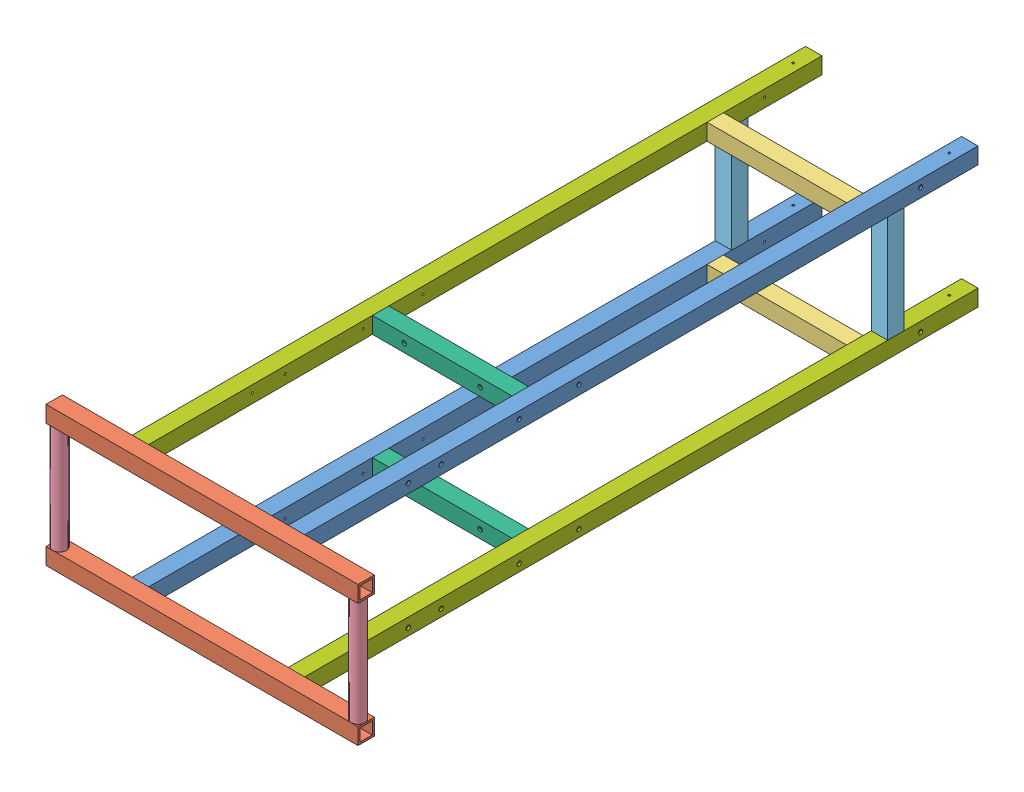
SolidWorks assembly GE-18054, configuration Default. Lengths in mm.
Overall size (978.32 431.8 2141.5).
14 component instances, 7 part files, 46 mates.
Components (placement in the parent):
- GE-18054-1-1: GE-18054-1 [Default] at (-50.8 0 0) size (50.8 50.8 2082.8)
- GE-18054-1-2: GE-18054-1 [Default] at (50.8 0 0) x (-1 0 0) z (0 0 1) size (50.8 50.8 2082.8)
- GE-18054-7-1: GE-18054-7 [Default] at (-266.7 -381 0) x (0 -1 0) z (0 0 1) size (50.8 965.2 50.8)
- GE-18054-7-2: GE-18054-7 [Default] at (-266.7 0 0) x (0 -1 0) z (0 0 1) size (50.8 965.2 50.8)
- GE-18054-3-1: GE-18054-3 [Default] at (-50.8 -381 304.8) x (0 -1 0) z (0 0 1) size (50.8 431.8 50.8)
- GE-18054-3-2: GE-18054-3 [Default] at (50.8 381 304.8) x (0 1 0) z (0 0 1) size (50.8 431.8 50.8)
- GE-18054-6-1: GE-18054-6 [Default] at (-1502.8409 0 1311.2812) x (0 -1 0) z (0.956707 0 0.291052) size (330.2 42.16 42.16)
- GE-18054-6-2: GE-18054-6 [Default] at (474.15 0 4016.5169) x (0 -1 0) z (-0.521598 0 -0.853191) size (330.2 42.16 42.16)
- GE-18054-5-1: GE-18054-5 [Default] at (431.8 0 228.6) x (0 -1 0) z (0 0 1) size (330.2 50.8 50.8)
- GE-18054-5-2: GE-18054-5 [Default] at (-431.8 0 228.6) x (0 1 0) z (0 0 1) size (330.2 50.8 50.8)
- GE-18054-4-1: GE-18054-4 [Default] at (50.8 381 781.05) x (0 1 0) z (0 0 1) size (50.8 431.8 50.8)
- GE-18054-4-2: GE-18054-4 [Default] at (-50.8 -381 781.05) x (0 -1 0) z (0 0 1) size (50.8 431.8 50.8)
- GE-18054-2-1: GE-18054-2 [Default] at (-50.8 0 0) size (50.8 50.8 2082.8)
- GE-18054-2-2: GE-18054-2 [Default] at (50.8 0 0) x (-1 0 0) z (0 0 1) size (50.8 50.8 2082.8)
Mates (geometry in assembly coordinates):
- Coincident1: coincident aligned: plane of GE-18054-1-1 through (-353.114 -215.9 2082.8) normal (0 -1 0); plane of GE-18054-3-1 through (104.086 -215.9 2387.6) normal (0 -1 0)
- Coincident2: coincident anti-aligned: plane of GE-18054-1-1 through (-353.114 -190.5 2082.8) normal (0 0 1); plane of GE-18054-7-1 through (370.786 -190.5 2082.8) normal (0 0 -1)
- Coincident3: coincident anti-aligned: plane of GE-18054-1-1 through (-327.714 -190.5 2082.8) normal (1 0 0); plane of GE-18054-4-2 through (-327.714 -190.5 1390.65) normal (-1 0 0)
- Coincident4: coincident aligned: plane of GE-18054-1-2 through (129.486 215.9 2082.8) normal (0 1 0); plane of GE-18054-7-2 through (370.786 215.9 2104.5987) normal (0 1 0)
- Coincident5: coincident anti-aligned: plane of GE-18054-1-2 through (129.486 190.5 2082.8) normal (0 0 1); plane of GE-18054-7-2 through (370.786 190.5 2082.8) normal (0 0 -1)
- Coincident6: coincident anti-aligned: plane of GE-18054-1-2 through (104.086 190.5 2082.8) normal (-1 0 0); plane of GE-18054-4-1 through (104.086 190.5 1390.65) normal (1 0 0)
- Coincident7: coincident aligned: plane of GE-18054-1-1 through (-353.114 -165.1 2082.8) normal (0 1 0); plane of GE-18054-7-1 through (370.786 -165.1 2104.5987) normal (0 1 0)
- Coincident8: coincident anti-aligned: plane of GE-18054-7-1 through (370.786 -165.1 2104.5987) normal (0 1 0); plane of GE-18054-6-2 through (-964.843 -165.1 2356.9289) normal (0 -1 0)
- Coincident9: coincident aligned: plane of GE-18054-7-1 through (-594.414 -190.5 1066.8) normal (-1 0 0); plane of GE-18054-7-2 through (-594.414 190.5 1066.8) normal (-1 0 0)
- Coincident10: coincident anti-aligned: plane of GE-18054-7-1 through (370.786 -190.5 2082.8) normal (0 0 -1); plane of GE-18054-2-2 through (129.486 -190.5 2082.8) normal (0 0 1)
- Coincident11: coincident anti-aligned: plane of GE-18054-7-2 through (370.786 165.1 2104.5987) normal (0 -1 0); plane of GE-18054-6-2 through (-964.843 165.1 2356.9289) normal (0 1 0)
- Coincident12: coincident anti-aligned: plane of GE-18054-7-2 through (370.786 190.5 2082.8) normal (0 0 -1); plane of GE-18054-2-1 through (-353.114 190.5 2082.8) normal (0 0 1)
- Lock1: lock: unknown of GE-18054-7-1; unknown of GE-18054-6-1
- Distance1: distance = 304.8 mm aligned: plane of GE-18054-3-1 through (215.9 -190.5 304.8) normal (0 0 -1); plane of GE-18054-2-2 through (241.3 -190.5 0) normal (0 0 -1)
- Coincident15: coincident anti-aligned: plane of GE-18054-3-1 through (104.086 -190.5 1346.2) normal (1 0 0); plane of GE-18054-2-2 through (104.086 -190.5 2082.8) normal (-1 0 0)
- Distance2: distance = 304.8 mm aligned: plane of GE-18054-3-2 through (-215.9 190.5 304.8) normal (0 0 -1); plane of GE-18054-2-1 through (-241.3 190.5 0) normal (0 0 -1)
- Coincident17: coincident anti-aligned: plane of GE-18054-3-2 through (-327.714 190.5 1346.2) normal (-1 0 0); plane of GE-18054-2-1 through (-327.714 190.5 2082.8) normal (1 0 0)
- Coincident18: coincident aligned: plane of GE-18054-3-2 through (-327.714 215.9 2387.6) normal (0 1 0); plane of GE-18054-2-1 through (-353.114 215.9 2082.8) normal (0 1 0)
- Tangent3: tangent aligned: plane of GE-18054-7-2 through (370.786 190.5 1066.8) normal (1 0 0); cylinder of GE-18054-6-1 through (349.704 -165.1 2112.518) axis (0 1 0) radius 21.082
- Tangent4: tangent aligned: plane of GE-18054-7-2 through (370.786 190.5 2133.6) normal (0 0 1); cylinder of GE-18054-6-1 through (349.704 -165.1 2112.518) axis (0 1 0) radius 21.082
- Coincident19: coincident anti-aligned: plane of GE-18054-7-2 through (370.786 165.1 2104.5987) normal (0 -1 0); plane of GE-18054-6-1 through (479.8987 165.1 1669.7237) normal (0 1 0)
- Lock2: lock: unknown of GE-18054-7-1; unknown of GE-18054-6-2
- Coincident20: coincident anti-aligned: plane of GE-18054-7-2 through (370.786 165.1 2104.5987) normal (0 -1 0); plane of GE-18054-6-2 through (-964.843 165.1 2356.9289) normal (0 1 0)
- Tangent7: tangent aligned: plane of GE-18054-7-2 through (370.786 190.5 2133.6) normal (0 0 1); cylinder of GE-18054-6-2 through (-573.332 -165.1 2112.518) axis (0 1 0) radius 21.082
- Tangent8: tangent aligned: plane of GE-18054-7-2 through (-594.414 190.5 1066.8) normal (-1 0 0); cylinder of GE-18054-6-2 through (-573.332 -165.1 2112.518) axis (0 1 0) radius 21.082
- Coincident21: coincident aligned: plane of GE-18054-1-1 through (-353.114 -215.9 2082.8) normal (0 -1 0); plane of GE-18054-4-2 through (-111.814 -215.9 1390.65) normal (0 -1 0)
- Width1: width anti-aligned: plane of GE-18054-1-1 through (-378.514 -190.5 2082.8) normal (-1 0 0); plane of GE-18054-2-2 through (154.886 -190.5 2082.8) normal (1 0 0); plane of GE-18054-7-1 through (370.786 -190.5 1066.8) normal (1 0 0); plane of GE-18054-7-1 through (-594.414 -190.5 1066.8) normal (-1 0 0)
- Distance4: distance = 228.6 mm aligned: plane of GE-18054-5-1 through (241.3 -165.1 228.6) normal (0 0 -1); plane of GE-18054-2-2 through (241.3 -190.5 0) normal (0 0 -1)
- Coincident23: coincident aligned: plane of GE-18054-5-1 through (154.886 -165.1 2311.4) normal (1 0 0); plane of GE-18054-2-2 through (154.886 -190.5 2082.8) normal (1 0 0)
- Coincident24: coincident anti-aligned: plane of GE-18054-5-1 through (129.486 -165.1 1270) normal (0 -1 0); plane of GE-18054-2-2 through (129.486 -165.1 2082.8) normal (0 1 0)
- Coincident25: coincident aligned: plane of GE-18054-5-2 through (-378.514 165.1 2311.4) normal (-1 0 0); plane of GE-18054-2-1 through (-378.514 190.5 2082.8) normal (-1 0 0)
- Coincident26: coincident anti-aligned: plane of GE-18054-5-2 through (-353.114 165.1 1270) normal (0 1 0); plane of GE-18054-2-1 through (-353.114 165.1 2082.8) normal (0 -1 0)
- Coincident27: coincident aligned: plane of GE-18054-5-1 through (129.486 -165.1 228.6) normal (0 0 -1); plane of GE-18054-5-2 through (-353.114 165.1 228.6) normal (0 0 -1)
- Distance5: distance = 1339.85 mm aligned: plane of GE-18054-4-1 through (0 190.5 1339.85) normal (0 0 -1); plane of GE-18054-2-1 through (-241.3 190.5 0) normal (0 0 -1)
- Coincident29: coincident anti-aligned: plane of GE-18054-1-2 through (104.086 190.5 2082.8) normal (-1 0 0); plane of GE-18054-3-2 through (104.086 190.5 1346.2) normal (1 0 0)
- Coincident30: coincident aligned: plane of GE-18054-1-2 through (129.486 215.9 2082.8) normal (0 1 0); plane of GE-18054-4-1 through (-111.814 215.9 1390.65) normal (0 1 0)
- Coincident31: coincident aligned: plane of GE-18054-1-1 through (-353.114 -215.9 2082.8) normal (0 -1 0); plane of GE-18054-4-2 through (-111.814 -215.9 1390.65) normal (0 -1 0)
- Coincident32: coincident anti-aligned: plane of GE-18054-4-2 through (104.086 -190.5 1390.65) normal (1 0 0); plane of GE-18054-2-2 through (104.086 -190.5 2082.8) normal (-1 0 0)
- Coincident33: coincident aligned: plane of GE-18054-4-2 through (-111.814 -215.9 1390.65) normal (0 -1 0); plane of GE-18054-2-2 through (129.486 -215.9 2082.8) normal (0 -1 0)
- Coincident35: coincident aligned: plane of GE-18054-4-1 through (-111.814 190.5 1339.85) normal (0 0 -1); plane of GE-18054-4-2 through (-111.814 -190.5 1339.85) normal (0 0 -1)
- Coincident36: coincident anti-aligned: plane of GE-18054-7-2 through (370.786 190.5 2082.8) normal (0 0 -1); plane of GE-18054-2-1 through (-353.114 190.5 2082.8) normal (0 0 1)
- Coincident37: coincident aligned: plane of GE-18054-7-2 through (370.786 215.9 2104.5987) normal (0 1 0); plane of GE-18054-2-1 through (-353.114 215.9 2082.8) normal (0 1 0)
- Coincident38: coincident aligned: plane of GE-18054-1-1 through (-378.514 -190.5 2082.8) normal (-1 0 0); plane of GE-18054-2-1 through (-378.514 190.5 2082.8) normal (-1 0 0)
- Coincident39: coincident anti-aligned: plane of GE-18054-2-2 through (129.486 -190.5 0) normal (0 0 -1); plane of assembly through (0 0 0) normal (0 0 1)
- Symmetric2: symmetric aligned: plane of ? through (129.486 215.9 2082.8) normal (0 1 0); plane of ? through (129.486 -215.9 2082.8) normal (0 -1 0)
- Symmetric3: symmetric aligned: plane of ? through (-266.7 -190.5 2082.8) normal (-1 0 0); plane of ? through (266.7 -190.5 2082.8) normal (1 0 0)
